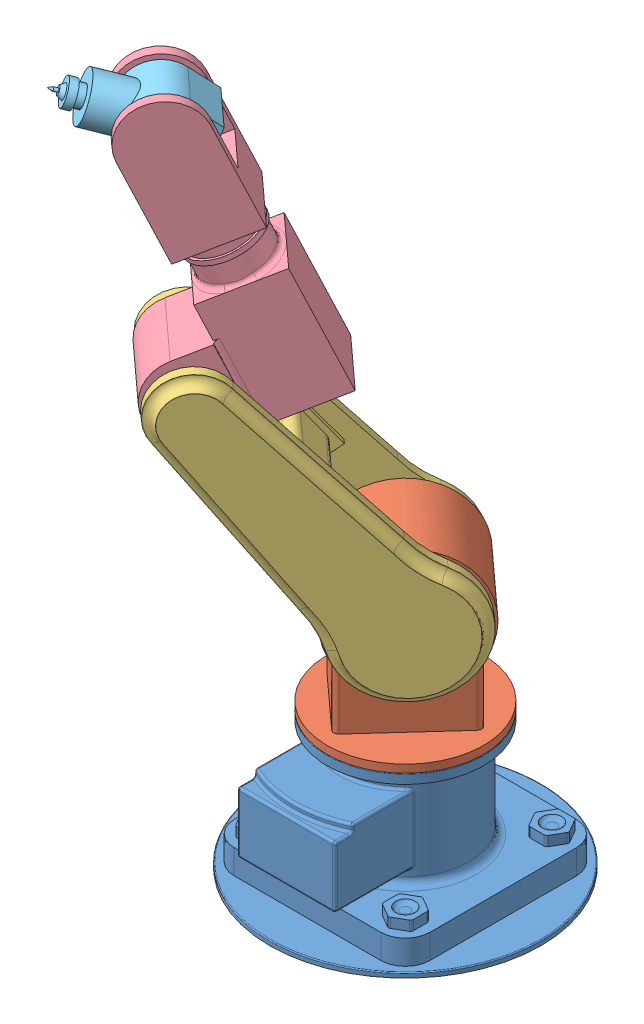
SolidWorks assembly Assem1, configuration Default. Lengths in mm.
Overall size (738.12 1453.4 757.75).
5 component instances, 5 part files, 8 mates.
Components (placement in the parent):
- base-1: base [Default] at (183.1433 139.865 445.3205) size (555 280 555)
- Link 01-1: Link 01 [Default] at (183.1433 299.865 445.3205) x (-0.672936 0 0.7397) z (-0.7397 0 -0.672936) size (320 466 320)
- Link 02-1: Link 02 [Default] at (183.1433 635.865 445.3205) x (-0.525076 -0.625436 0.57717) z (-0.7397 0 -0.672936) size (250 700 260.14)
- Link 03-1: Link 03 [Default] at (78.7793 999.1644 545.1785) x (-0.270238 0.915824 0.297049) z (-0.7397 0 -0.672936) size (595 296.15 160)
- Link 04-1: Link 04 [Default] at (-61.7445 1475.3927 699.6442) x (-0.637124 0.321877 0.700335) z (0.7397 0 0.672936) size (255 130 100)
Mates (geometry in assembly coordinates):
- Concentric1: concentric anti-aligned: cylinder of base-1 through (183.1433 219.865 445.3205) axis (0 1 0) radius 100; cylinder of Link 01-1 through (183.1433 419.865 445.3205) axis (0 -1 0) radius 100
- Coincident1: coincident anti-aligned: plane of base-1 through (183.1433 419.865 445.3205) normal (0 1 0); plane of Link 01-1 through (183.1433 419.865 445.3205) normal (0 -1 0)
- Concentric2: concentric aligned: cylinder of Link 01-1 through (128.9219 635.865 373.4871) axis (0.60246 0 0.798149) radius 75; cylinder of Link 02-1 through (128.9219 635.865 373.4871) axis (0.60246 0 0.798149) radius 75
- Coincident2: coincident anti-aligned: plane of Link 01-1; plane of Link 02-1
- Concentric3: concentric aligned: cylinder of Link 02-1 through (-54.7937 1079.7327 512.1594) axis (0.60246 0 0.798149) radius 50; cylinder of Link 03-1 through (-54.7937 1079.7327 512.1594) axis (0.60246 0 0.798149) radius 50
- Coincident3: coincident anti-aligned: plane of Link 02-1; plane of Link 03-1
- Concentric5: concentric anti-aligned: cylinder of Link 03-1 through (254.5841 1310.6387 278.6321) axis (0.60246 0 0.798149) radius 50; cylinder of Link 04-1 through (332.9051 1310.6387 382.3931) axis (-0.60246 0 -0.798149) radius 50
- Coincident5: coincident anti-aligned: plane of Link 03-1; plane of Link 04-1
